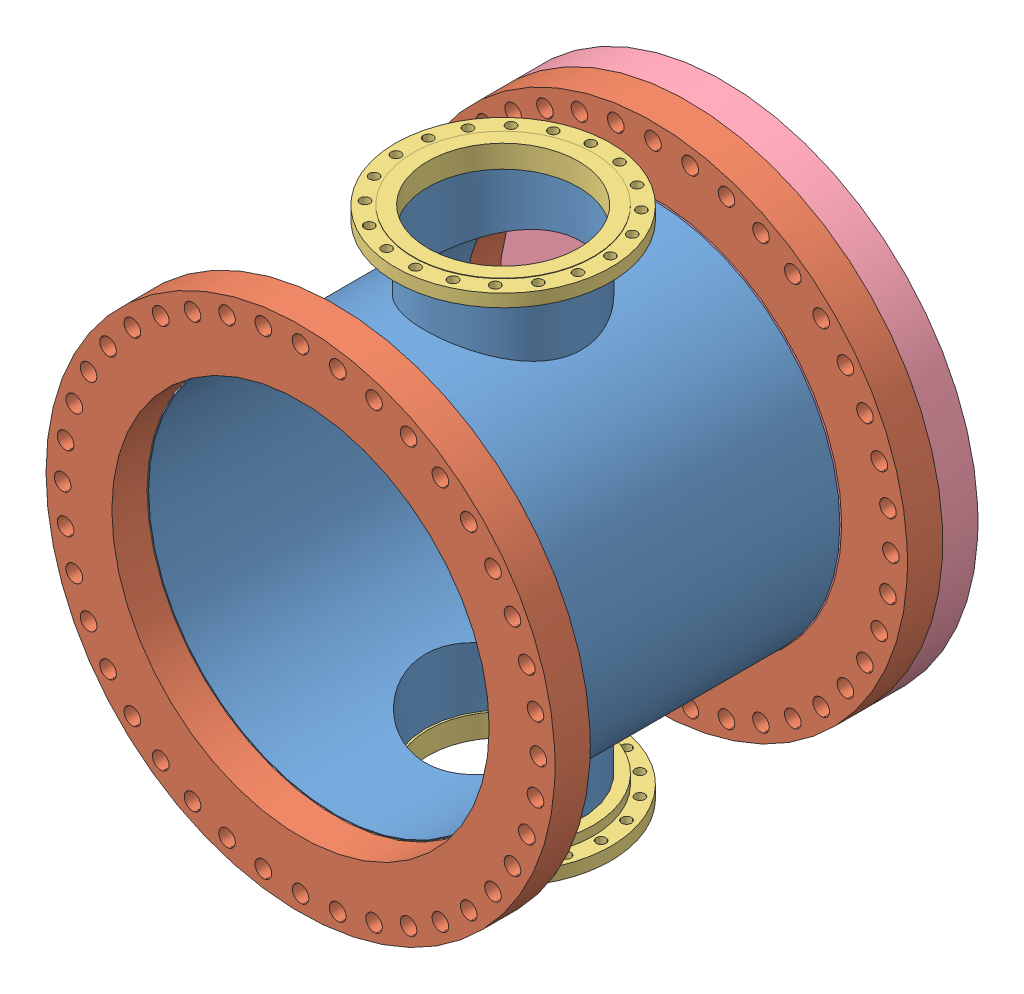
SolidWorks assembly HeatExchanger_48in_section_AB_Assembly, configuration Default. Lengths in mm.
Overall size (1651 1669.92 1371.62).
6 component instances, 4 part files, 8 mates.
Components (placement in the parent):
- HeatExchanger_48in_Section_AB-1: HeatExchanger_48in_Section_AB [Default] at origin size (1219.2 1524 1025.4)
- AWWA_C207_18 Class_F_RING_48in_Flange-1: AWWA_C207_18 Class_F_RING_48in_Flange [Default] at (-0.0089 0.0007 588.9455) size (1651 1651 114.3)
- AWWA_C207_18 Class_F_RING_48in_Flange-2: AWWA_C207_18 Class_F_RING_48in_Flange [Default] at (-0.0089 0.0007 -554.0712) size (1651 1651 114.3)
- ANSIASME_20in_150RSFO_Flange-1: ANSIASME_20in_150RSFO_Flange [Default] at (-0.0089 -803.8867 -8.7525) x (1 0 0) z (0 -1 0) size (698.5 698.5 72.96)
- ANSIASME_20in_150RSFO_Flange-2: ANSIASME_20in_150RSFO_Flange [Default] at (-0.0089 803.8882 -8.7525) x (-0.91543 0 0.402477) z (0 1 0) size (698.5 698.5 72.96)
- 48in_Flange_Blind-1: 48in_Flange_Blind [Default] at (-0.0089 0.0007 -668.3712) size (1651 1651 114.3)
Mates (geometry in assembly coordinates):
- Concentric1: concentric aligned: circle of HeatExchanger_48in_Section_AB-1; circle of AWWA_C207_18 Class_F_RING_48in_Flange-1
- Coincident1: coincident anti-aligned: plane of HeatExchanger_48in_Section_AB-1 through (-0.0089 0.0007 534.0455) normal (0 0 1); plane of AWWA_C207_18 Class_F_RING_48in_Flange-1 through (-0.0089 0.0007 534.0455) normal (0 0 -1)
- Concentric2: concentric aligned: circle of HeatExchanger_48in_Section_AB-1; circle of AWWA_C207_18 Class_F_RING_48in_Flange-2
- Concentric4: concentric anti-aligned: circle of HeatExchanger_48in_Section_AB-1; circle of ANSIASME_20in_150RSFO_Flange-1
- Coincident3: coincident anti-aligned: plane of HeatExchanger_48in_Section_AB-1 through (-0.0089 -761.9993 -8.7525) normal (0 -1 0); plane of ANSIASME_20in_150RSFO_Flange-1 through (-0.0089 -761.9993 -8.7525) normal (0 1 0)
- Concentric8: concentric: circle of HeatExchanger_48in_Section_AB-1; circle of ANSIASME_20in_150RSFO_Flange-2
- Coincident4: coincident anti-aligned: plane of HeatExchanger_48in_Section_AB-1 through (-0.0089 762.0007 -8.7525) normal (0 1 0); plane of ANSIASME_20in_150RSFO_Flange-2 through (-0.0089 762.0007 -8.7525) normal (0 -1 0)
- Coincident5: coincident aligned: circle of AWWA_C207_18 Class_F_RING_48in_Flange-2; circle of 48in_Flange_Blind-1
